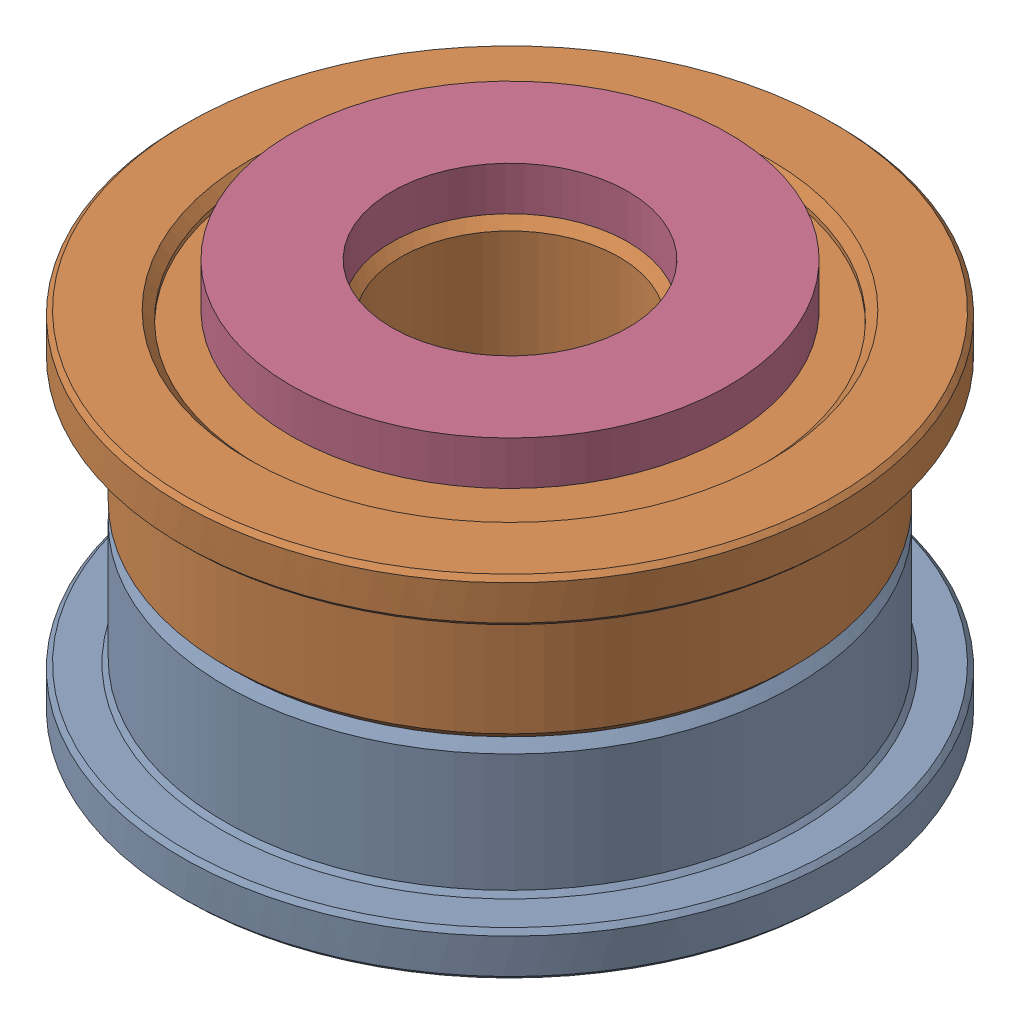
SolidWorks assembly Idler Pulley Assembly v3 (1)_1, configuration Default. Lengths in mm.
Overall size (15 10 15).
4 component instances, 3 part files, 0 mates.
Components (placement in the parent):
- F695-2RS v1 (1) (1)-1: F695-2RS v1 (1) (1) [Default] at origin size (15 4 15)
- F695-2RS v1 (2) (1)-1: F695-2RS v1 (2) (1) [Default] at (0 8 0) x (-1 0 0) z (0 0 1) size (15 4 15)
- M5 1mm Spacer (2)-1: M5 1mm Spacer (2) [Default] at (0 0 350) size (10 1 10)
- M5 1mm Spacer (2)-2: M5 1mm Spacer (2) [Default] at (0 9 350) size (10 1 10)
